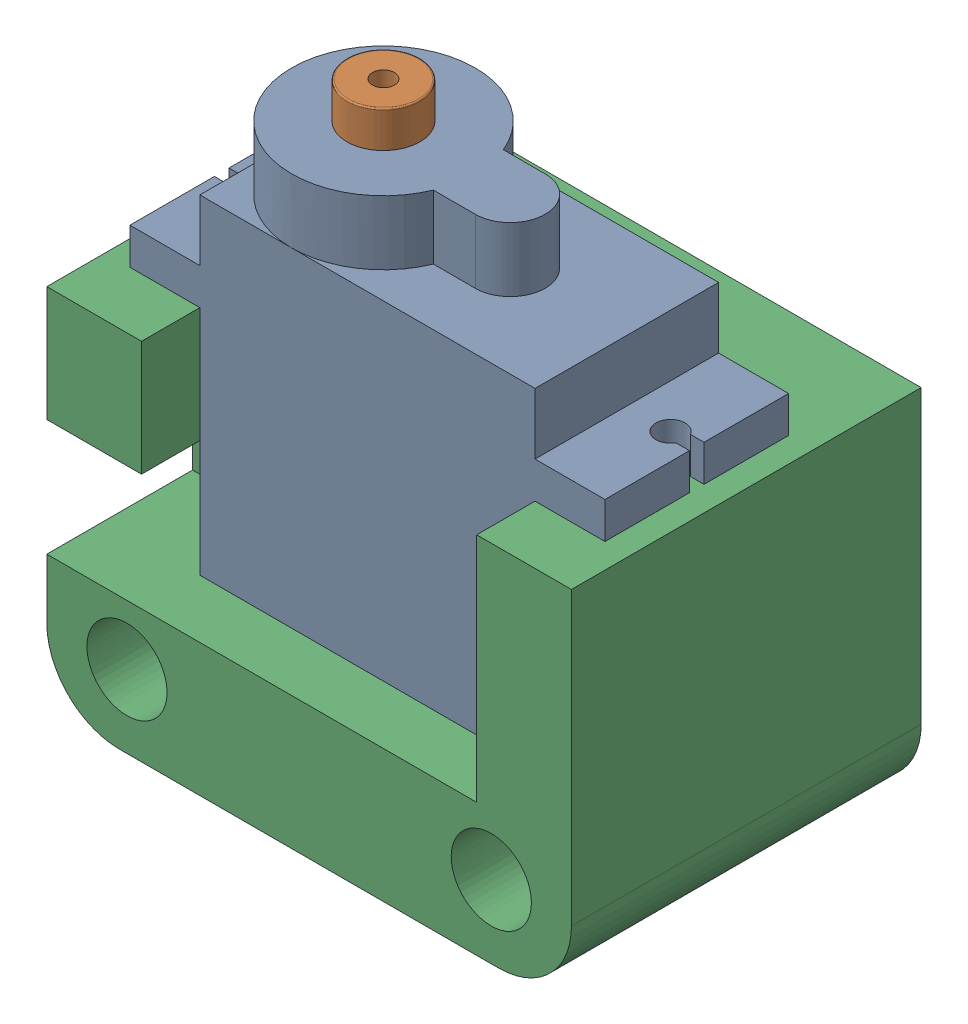
SolidWorks assembly 03-01-servo_assembly, configuration Default. Lengths in mm.
3 component instances, 3 part files, 5 mates.
Components (placement in the parent):
- 03-01-servo_body-1: 03-01-servo_body [Predeterminado] at (10.9921 2.7063 24.2695) size (32.6 27 12.6)
- 03-01-servo_shaft-1: 03-01-servo_shaft [Predeterminado] at (5.7921 25.3063 30.5695) x (0.964787 0 0.263033) z (-0.263033 0 0.964787) size (4.99 6.9 4.99)
- 02-01-servo_block-1: 02-01-servo_block [Default] at (-7.0079 -6.3937 16.8695) x (1 0 0) z (0 -1 0) size (36 24 25)
Mates (geometry in assembly coordinates):
- Concentric1: concentric: cylinder of 03-01-servo_body-1 through (5.7921 29.7063 34.5695) axis (0 -1 0) radius 2.5; cylinder of 03-01-servo_shaft-1 through (5.7921 32.2063 34.5695) axis (0 -1 0) radius 2.495
- Coincident1: coincident: plane of 03-01-servo_body-1 through (-0.5079 25.3063 40.8695) normal (0 1 0); plane of 03-01-servo_shaft-1 through (5.7921 25.3063 34.5695) normal (0 -1 0)
- Concentric2: concentric: cylinder of 03-01-servo_body-1 through (25.4921 18.6063 34.5695) axis (0 1 0) radius 1; cylinder of 02-01-servo_block-1 through (25.4921 18.6063 34.5695) axis (0 1 0) radius 1.025
- Concentric3: concentric: cylinder of 03-01-servo_body-1 through (-3.5079 18.6063 34.5695) axis (0 1 0) radius 1; cylinder of 02-01-servo_block-1 through (-3.5079 18.6063 34.5695) axis (0 1 0) radius 1.025
- Coincident2: coincident: plane of 03-01-servo_body-1 through (22.4921 2.7063 40.8695) normal (0 -1 0); plane of 02-01-servo_block-1 through (-0.5079 2.7063 28.2695) normal (0 1 0)
